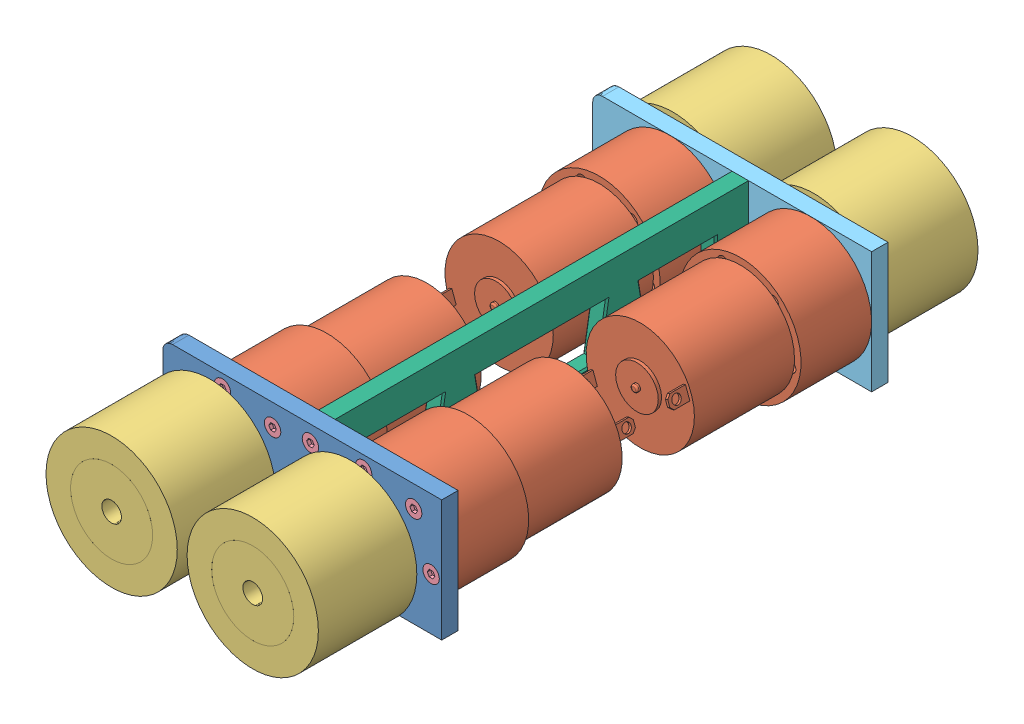
SolidWorks assembly Tren_Trasero, configuration Predeterminado. Lengths in mm.
Overall size (88.08 45.36 282.25).
41 component instances, 6 part files, 9 mates.
Components (placement in the parent):
- Ruedas_D-1: Ruedas_D [Predeterminado] at (3.9847 -7.6146 27.875) size (88.08 41.65 151.25)
  - Bracket_Motor_D-1: Bracket_Motor_D [Predeterminado] at (-5.4362 4.6538 77.5) size (85 37 5)
  - Titan-37mm-500rpm-2: Titan-37mm-500rpm [Predeterminado] at (16.0638 4.6538 56) x (0.34202 -0.939693 0) z (0 0 1) size (37 37 78.75)
  - Titan-37mm-500rpm-3: Titan-37mm-500rpm [Predeterminado] at (-26.9341 4.6545 56) x (0.34202 -0.939693 0) z (0 0 1) size (37 37 78.75)
  - js4030-wheel-cad-1: js4030-wheel-cad [Predeterminado] at (-53.7606 2.8053 140) x (-1 0 0) z (0 0 -1) size (40 40 30)
  - js4030-wheel-cad-2: js4030-wheel-cad [Predeterminado] at (-10.7627 2.8046 140) x (-1 0 0) z (0 0 -1) size (40 40 30)
  - Tornillo M3x15-1: Tornillo M3x15 [Predeterminado] at (-42.2008 7.3453 67.5) size (5 5 15.24)
  - Tornillo M3x15-2: Tornillo M3x15 [Predeterminado] at (-32.2376 19.219 67.5) size (5 5 15.24)
  - Tornillo M3x15-4: Tornillo M3x15 [Predeterminado] at (-21.6349 -9.9115 67.5) size (5 5 15.24)
  - Tornillo M3x15-5: Tornillo M3x15 [Predeterminado] at (-36.8995 -7.2199 67.5) size (5 5 15.24)
  - Tornillo M3x15-6: Tornillo M3x15 [Predeterminado] at (-16.973 16.5274 67.5) size (5 5 15.24)
  - Tornillo M3x15-7: Tornillo M3x15 [Predeterminado] at (-11.6717 1.9622 67.5) size (5 5 15.24)
  - Tornillo M3x15-8: Tornillo M3x15 [Predeterminado] at (6.1005 -7.2199 67.5) size (5 5 15.24)
  - Tornillo M3x15-9: Tornillo M3x15 [Predeterminado] at (31.3283 1.9622 67.5) size (5 5 15.24)
  - Tornillo M3x15-10: Tornillo M3x15 [Predeterminado] at (21.3651 -9.9115 67.5) size (5 5 15.24)
  - Tornillo M3x15-11: Tornillo M3x15 [Predeterminado] at (0.7992 7.3453 67.5) size (5 5 15.24)
  - Tornillo M3x15-12: Tornillo M3x15 [Predeterminado] at (26.027 16.5274 67.5) size (5 5 15.24)
  - Tornillo M3x15-13: Tornillo M3x15 [Predeterminado] at (10.7624 19.219 67.5) size (5 5 15.24)
- Ruedas_I-1: Ruedas_I [Predeterminado] at (17.4264 0.7496 -103.125) size (88.08 44.6 128.99)
  - Bracket_Motor_I-1: Bracket_Motor_I [Predeterminado] at (-18.8779 -3.7105 77.5) size (85 37 5)
  - Titan-37mm-500rpm-3: Titan-37mm-500rpm [Predeterminado] at (2.6242 -3.7097 104) x (-0.34202 0.939693 0) z (0 0 -1) size (37 37 78.75)
  - Titan-37mm-500rpm-4: Titan-37mm-500rpm [Predeterminado] at (-40.3758 -3.7097 104) x (-0.34202 0.939693 0) z (0 0 -1) size (37 37 78.75)
  - Tornillo M3x15-1: Tornillo M3x15 [Predeterminado] at (-45.6792 10.8547 92.5) x (-1 0 0) z (0 0 -1) size (5 5 15.24)
  - Tornillo M3x15-2: Tornillo M3x15 [Predeterminado] at (-30.4147 8.1632 92.5) x (-1 0 0) z (0 0 -1) size (5 5 15.24)
  - Tornillo M3x15-3: Tornillo M3x15 [Predeterminado] at (-25.1134 -6.402 92.5) x (-1 0 0) z (0 0 -1) size (5 5 15.24)
  - Tornillo M3x15-4: Tornillo M3x15 [Predeterminado] at (-35.0766 -18.2757 92.5) x (-1 0 0) z (0 0 -1) size (5 5 15.24)
  - Tornillo M3x15-5: Tornillo M3x15 [Predeterminado] at (-50.3411 -15.5842 92.5) x (-1 0 0) z (0 0 -1) size (5 5 15.24)
  - Tornillo M3x15-6: Tornillo M3x15 [Predeterminado] at (17.8866 -6.402 92.5) x (-1 0 0) z (0 0 -1) size (5 5 15.24)
  - Tornillo M3x15-7: Tornillo M3x15 [Predeterminado] at (-7.3411 -15.5842 92.5) x (-1 0 0) z (0 0 -1) size (5 5 15.24)
  - Tornillo M3x15-8: Tornillo M3x15 [Predeterminado] at (-12.6424 -1.0189 92.5) x (-1 0 0) z (0 0 -1) size (5 5 15.24)
  - Tornillo M3x15-9: Tornillo M3x15 [Predeterminado] at (-55.6424 -1.0189 92.5) x (-1 0 0) z (0 0 -1) size (5 5 15.24)
  - Tornillo M3x15-10: Tornillo M3x15 [Predeterminado] at (12.5853 8.1632 92.5) x (-1 0 0) z (0 0 -1) size (5 5 15.24)
  - Tornillo M3x15-11: Tornillo M3x15 [Predeterminado] at (7.9234 -18.2757 92.5) x (-1 0 0) z (0 0 -1) size (5 5 15.24)
  - Tornillo M3x15-12: Tornillo M3x15 [Predeterminado] at (-2.6792 10.8547 92.5) x (-1 0 0) z (0 0 -1) size (5 5 15.24)
  - js4030-wheel-cad-1: js4030-wheel-cad [Predeterminado] at (16.2907 -5.5589 20) size (40 40 30)
  - js4030-wheel-cad-2: js4030-wheel-cad [Predeterminado] at (-26.7093 -5.5589 20) size (40 40 30)
- Struct_1-1: Struct_1 [Predeterminado] at (-1.4515 10.5391 -20.625) size (5 37 126)
- Tornillo M3x15-5: Tornillo M3x15 [Predeterminado] at (-1.4515 -16.4609 95.375) size (5 5 15.24)
- Tornillo M3x15-6: Tornillo M3x15 [Predeterminado] at (-1.4515 10.5391 95.375) size (5 5 15.24)
- Tornillo M3x15-7: Tornillo M3x15 [Predeterminado] at (-1.4515 -16.4609 -10.625) x (-1 0 0) z (0 0 -1) size (5 5 15.24)
- Tornillo M3x15-8: Tornillo M3x15 [Predeterminado] at (-1.4515 10.5391 -10.625) x (-1 0 0) z (0 0 -1) size (5 5 15.24)
Mates (geometry in assembly coordinates):
- Concéntrica1: concentric anti-aligned: cylinder of Ruedas_D-1/js4030-wheel-cad-1 through (-29.5293 -5.355 112.875) axis (0 0 1) radius 3; cylinder of Ruedas_I-1/js4030-wheel-cad-2 through (-29.5293 -5.355 -28.125) axis (0 0 -1) radius 3
- Distancia1: distance = 136 mm anti-aligned: plane of Ruedas_I-1/Bracket_Motor_I-1 through (-1.4515 -2.9609 -25.625) normal (0 0 -1); plane of Ruedas_D-1/Bracket_Motor_D-1 through (-1.4515 -2.9609 110.375) normal (0 0 1)
- Distancia2: distance = 37.5 mm aligned: plane of Struct_1-1 through (1.0485 5.5391 105.375) normal (1 0 0); plane of Ruedas_D-1/Bracket_Motor_D-1 through (38.5485 -21.4609 110.375) normal (1 0 0)
- Coincidente3: coincident aligned: plane of Ruedas_D-1/Bracket_Motor_D-1 through (-41.4515 15.5391 110.375) normal (0 1 0); plane of Struct_1-1 through (-3.9515 15.5391 105.375) normal (0 1 0)
- Coincidente4: coincident anti-aligned: plane of Ruedas_D-1/Bracket_Motor_D-1 through (-1.4515 -2.9609 105.375) normal (0 0 -1); plane of Struct_1-1 through (-1.4515 10.5391 105.375) normal (0 0 1)
- Coincidente5: coincident aligned: cone of Ruedas_D-1/Bracket_Motor_D-1 through (-1.4515 -16.4609 108.375) axis (0 0 -1); cone of Tornillo M3x15-5 through (-1.4515 -16.4609 109.875) axis (0 0 -1)
- Coincidente6: coincident aligned: cone of Ruedas_D-1/Bracket_Motor_D-1 through (-1.4515 10.5391 108.375) axis (0 0 -1); cone of Tornillo M3x15-6 through (-1.4515 10.5391 109.875) axis (0 0 -1)
- Coincidente7: coincident aligned: cone of Ruedas_I-1/Bracket_Motor_I-1 through (-1.4515 -16.4609 -23.625) axis (0 0 1); cone of Tornillo M3x15-7 through (-1.4515 -16.4609 -25.125) axis (0 0 1)
- Coincidente8: coincident aligned: cone of Ruedas_I-1/Bracket_Motor_I-1 through (-1.4515 10.5391 -23.625) axis (0 0 1); cone of Tornillo M3x15-8 through (-1.4515 10.5391 -25.125) axis (0 0 1)
